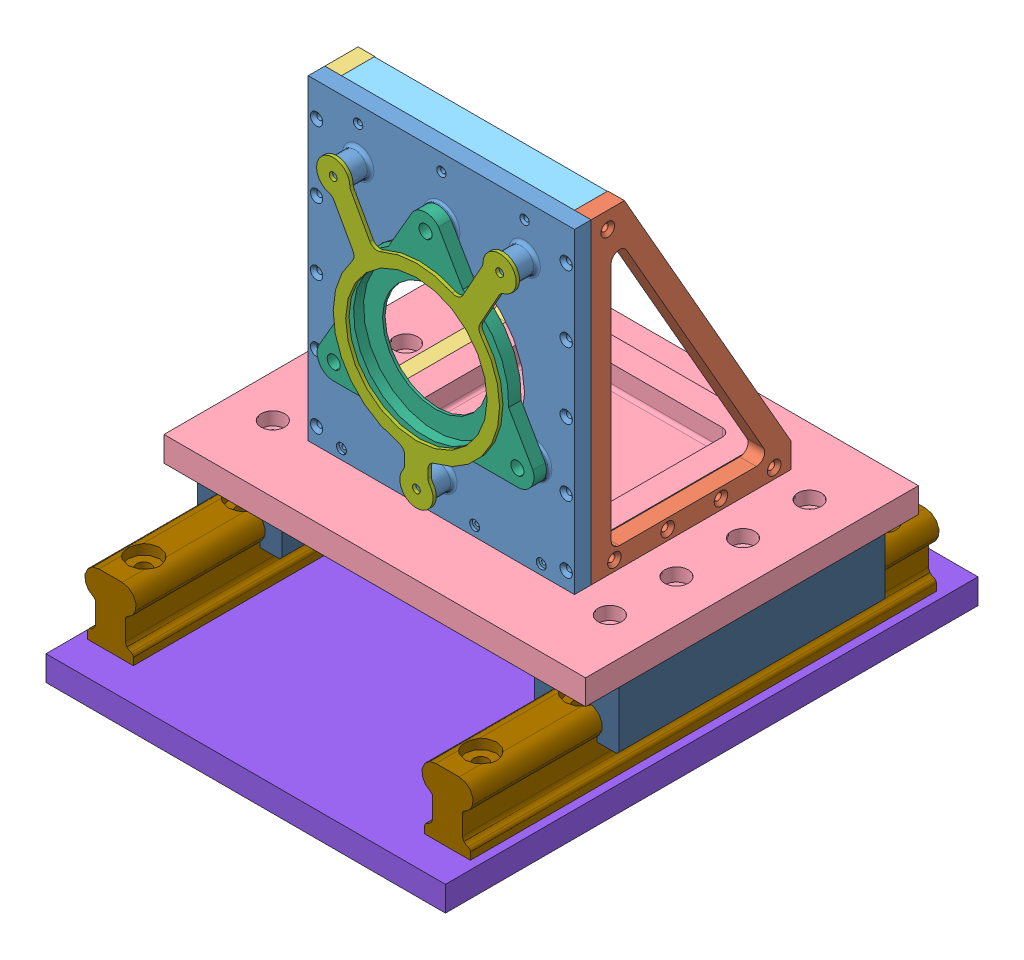
SolidWorks assembly lens_mount, configuration Default. Lengths in mm.
Overall size (321.69 351.78 406.4).
12 component instances, 10 part files, 31 mates.
Components (placement in the parent):
- frontplate-1: frontplate [Default] at (50.8 110.4814 244.4025) size (203.2 241.3 29.21)
- braceleft-1: braceleft [Default] at (241.3 110.4814 244.4025) x (0 0 -1) z (1 0 0) size (152.4 241.3 12.7)
- braceright-1: braceright [Default] at (50.8 110.4814 244.4025) x (0 0 -1) z (1 0 0) size (152.4 241.3 12.7)
- baseplate-1: baseplate [Default] at (-31.9265 110.4814 -158.66) x (1 0 0) z (0 -1 0) size (321.69 254 34.92)
- crossbar-1: crossbar [Default] at (50.8 136.2814 244.4025) x (-1 0 0) z (0 0 -1) size (177.8 25 25)
- lensholder-1: lensholder [Default] at (152.4 224.7814 259.6425) x (0 1 0) z (0 0 1) size (157.11 165.55 9.53)
- filterholder-1: filterholder [Default] at (152.4 139.0564 273.6125) size (152.4 200.02 2.54)
- table-1: table [Default] at (76.5912 0 305.9996) x (0 0 -1) z (0 1 0) size (406.4 304.8 19.05)
- rail-1: rail [left] at (6.35 19.05 25.4) size (39.12 50.8 355.6)
- rail-2: rail [right] at (263.525 19.05 25.4) size (39.12 50.8 355.6)
- slider-1: slider [left] at (60.0609 79.9184 79.3025) size (64.52 44.45 203.2)
- slider-3: slider [right] at (317.2359 79.9184 79.3025) size (64.52 44.45 203.2)
Mates (geometry in assembly coordinates):
- Coincident1: coincident anti-aligned: plane of frontplate-1 through (152.4 305.6942 259.6425) normal (0 0 1); plane of lensholder-1 through (152.4 224.7814 259.6425) normal (0 0 -1)
- Concentric1: concentric aligned: cylinder of frontplate-1 through (152.4 305.6942 259.6425) axis (0 0 -1) radius 12.7; cylinder of lensholder-1 through (152.4 305.6942 269.1675) axis (0 0 -1) radius 12.7
- Parallel1: parallel aligned: line of frontplate-1 through (50.8 110.4814 257.1025) axis (1 0 0); line of lensholder-1 through (80.4168 171.7696 269.1675) axis (1 0 0)
- Coincident2: coincident anti-aligned: plane of frontplate-1 through (215.9 313.6814 273.6125) normal (0 0 1); plane of filterholder-1 through (98.4238 269.1164 273.6125) normal (0 0 -1)
- Concentric2: concentric aligned: cylinder of frontplate-1 through (215.9 313.6814 273.6125) axis (0 0 -1) radius 9.525; cylinder of filterholder-1 through (215.9 313.6814 276.1525) axis (0 0 -1) radius 12.7
- Coincident3: coincident anti-aligned: plane of frontplate-1 through (50.8 351.7814 244.4025) normal (0 0 -1); plane of braceright-1 through (63.5 110.4814 244.4025) normal (0 0 1)
- Coincident4: coincident aligned: line of frontplate-1 through (50.8 351.7814 244.4025) axis (0 -1 0); line of braceright-1 through (50.8 351.7814 244.4025) axis (0 -1 0)
- Coincident5: coincident: point of frontplate-1; point of braceright-1
- Coincident6: coincident anti-aligned: plane of frontplate-1 through (50.8 351.7814 244.4025) normal (0 0 -1); plane of braceleft-1 through (254 110.4814 244.4025) normal (0 0 1)
- Coincident7: coincident anti-aligned: line of frontplate-1 through (254 110.4814 244.4025) axis (0 1 0); line of braceleft-1 through (254 351.7814 244.4025) axis (0 -1 0)
- Coincident8: coincident: point of frontplate-1; point of braceleft-1
- Coincident9: coincident anti-aligned: plane of frontplate-1 through (50.8 110.4814 257.1025) normal (0 -1 0); plane of baseplate-1 through (-8.4455 110.4814 53.9025) normal (0 1 0)
- Coincident10: coincident anti-aligned: plane of braceright-1 through (63.5 351.7814 244.4025) normal (1 0 0); plane of baseplate-1 through (63.5 126.3564 233.6139) normal (-1 0 0)
- Coincident11: coincident anti-aligned: plane of frontplate-1 through (50.8 351.7814 244.4025) normal (0 0 -1); plane of baseplate-1 through (73.2155 126.3564 244.4025) normal (0 0 1)
- Coincident12: coincident anti-aligned: plane of frontplate-1 through (50.8 351.7814 244.4025) normal (0 0 -1); plane of crossbar-1 through (63.5 326.7814 244.4025) normal (0 0 1)
- Coincident13: coincident anti-aligned: line of frontplate-1 through (254 351.7814 244.4025) axis (-1 0 0); line of crossbar-1 through (63.5 351.7814 244.4025) axis (1 0 0)
- Coincident14: coincident: line of braceleft-1 through (241.3 351.7814 219.0025) axis (0 0 1); point of crossbar-1
- Distance8: distance = 6.35 mm aligned: plane of table-1 through (0 19.05 406.4) normal (-1 0 0); plane of rail-1 through (6.35 19.05 381) normal (-1 0 0)
- Coincident40: coincident anti-aligned: plane of table-1 through (0 19.05 406.4) normal (0 1 0); plane of rail-1 through (6.35 19.05 381) normal (0 -1 0)
- Distance9: distance = 25.4 mm aligned: plane of table-1 through (304.8 19.05 406.4) normal (0 0 1); plane of rail-1 through (8.89 24.5201 381) normal (0 0 1)
- Distance10: distance = 6.35 mm aligned: plane of table-1 through (304.8 19.05 406.4) normal (1 0 0); plane of rail-2 through (298.45 19.05 381) normal (1 0 0)
- Coincident45: coincident anti-aligned: plane of table-1 through (0 19.05 406.4) normal (0 1 0); plane of rail-2 through (263.525 19.05 381) normal (0 -1 0)
- Coincident46: coincident aligned: plane of rail-1 through (8.89 24.5201 381) normal (0 0 1); plane of rail-2 through (266.065 24.5201 381) normal (0 0 1)
- Concentric4: concentric aligned: cylinder of rail-1 through (14.9225 59.182 381) axis (0 0 -1) radius 10.668; cylinder of slider-1 through (14.9225 59.182 282.5025) axis (0 0 -1) radius 10.668
- Concentric5: concentric aligned: cylinder of rail-1 through (32.7025 59.182 381) axis (0 0 -1) radius 10.668; cylinder of slider-1 through (32.7025 59.182 282.5025) axis (0 0 -1) radius 10.668
- Concentric6: concentric aligned: cylinder of rail-2 through (272.0975 59.182 381) axis (0 0 -1) radius 10.668; cylinder of slider-3 through (272.0975 59.182 282.5025) axis (0 0 -1) radius 10.668
- Concentric7: concentric aligned: cylinder of rail-2 through (289.8775 59.182 381) axis (0 0 -1) radius 10.668; cylinder of slider-3 through (289.8775 59.182 282.5025) axis (0 0 -1) radius 10.668
- Coincident47: coincident aligned: plane of slider-1 through (14.9225 59.182 282.5025) normal (0 0 1); plane of slider-3 through (272.0975 59.182 282.5025) normal (0 0 1)
- Coincident48: coincident anti-aligned: plane of baseplate-1 through (-8.4455 91.4314 53.9025) normal (0 -1 0); plane of slider-3 through (248.7295 91.4314 282.5025) normal (0 1 0)
- Coincident49: coincident anti-aligned: line of baseplate-1 through (313.2455 91.4314 53.9025) axis (0 0 1); line of slider-3 through (313.2455 91.4314 282.5025) axis (0 0 -1)
- Distance11: distance = 25.4 mm aligned: plane of baseplate-1 through (-8.4455 91.4314 307.9025) normal (0 0 1); plane of slider-1 through (14.9225 59.182 282.5025) normal (0 0 1)
